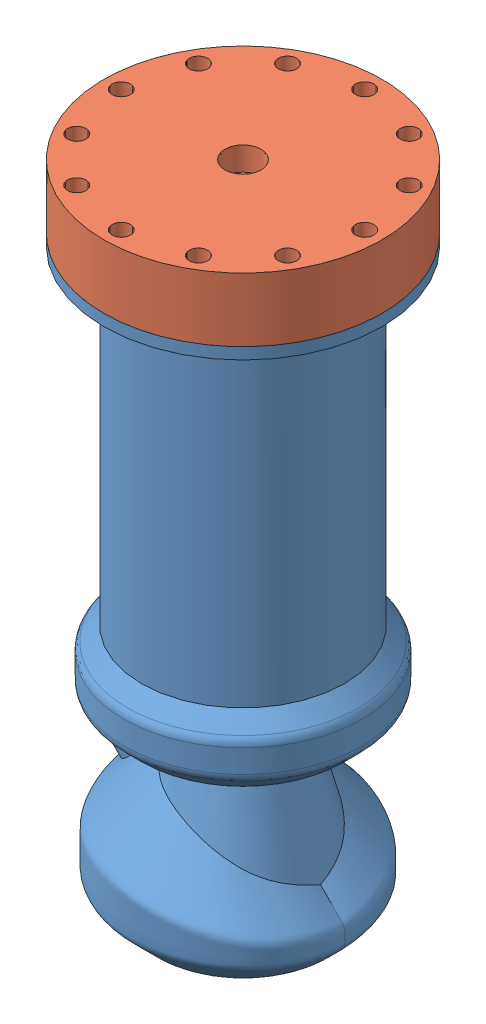
SolidWorks assembly regen addative impinging engine, configuration Default. Lengths in mm.
Overall size (152.4 398.41 152.4).
2 component instances, 2 part files, 4 mates.
Components (placement in the parent):
- slot cooling jacket 11-1: slot cooling jacket 11 [Default] at origin size (152.4 363.49 152.4)
- addative coax swirl injector-1: addative coax swirl injector [Default] at (0 -3.175 0) size (152.4 42.86 152.4)
Mates (geometry in assembly coordinates):
- Coincident1: coordinate: point of slot cooling jacket 11-1
- Concentric1: concentric anti-aligned: cylinder of slot cooling jacket 11-1 through (0 0 0) axis (0 -1 0) radius 46.0375; cylinder of addative coax swirl injector-1 through (0 34.925 0) axis (0 1 0) radius 76.2
- Coincident2: coincident anti-aligned: plane of slot cooling jacket 11-1 through (-46.0375 0 0) normal (0 1 0); plane of addative coax swirl injector-1 through (-76.2 0 0) normal (0 -1 0)
- Concentric2: concentric: cylinder of slot cooling jacket 11-1 through (33.3375 0 57.7422) axis (0 1 0) radius 5.0419; cylinder of addative coax swirl injector-1 through (33.3375 34.925 57.7422) axis (0 1 0) radius 5.0419
